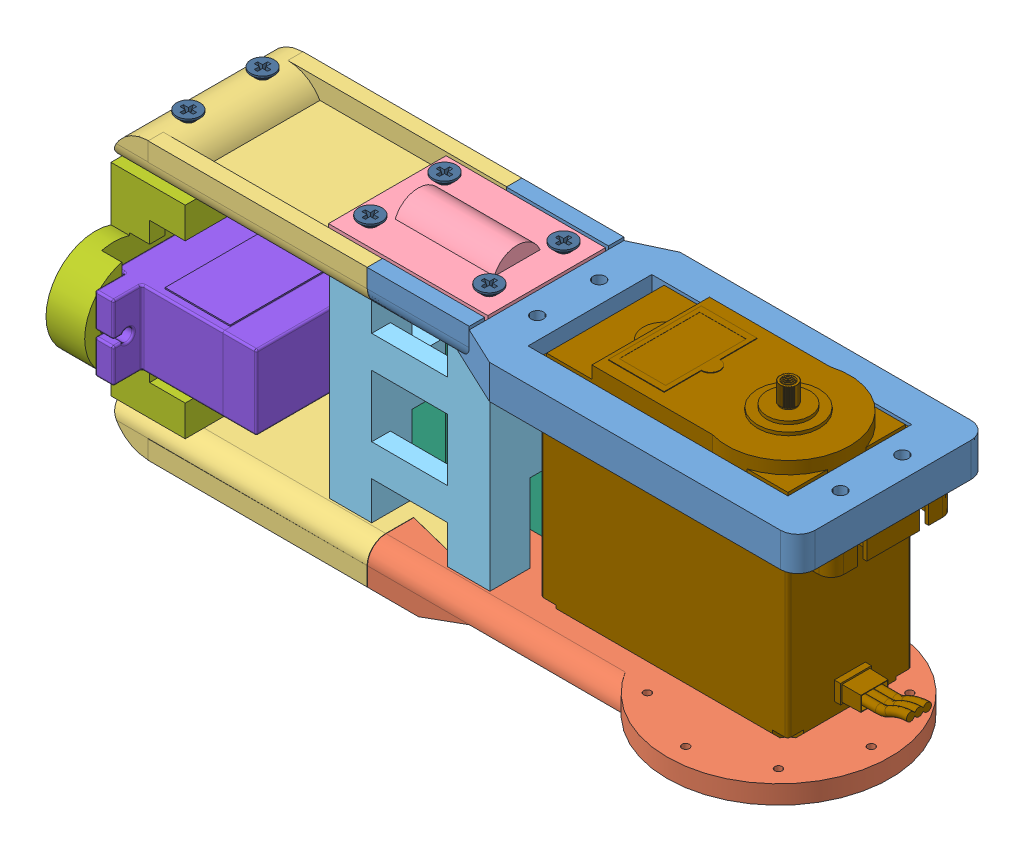
SolidWorks assembly Ensamblaje-Eslabon3, configuration Predeterminado. Lengths in mm.
Overall size (122.83 52.95 40.95).
25 component instances, 10 part files, 55 mates.
Components (placement in the parent):
- Eslabon3A-Servo-1: Eslabon3A-Servo [Predeterminado] at (-25.9252 12.8725 72.6169) size (72.49 6 30.8)
- Eslabon3B-1: Eslabon3B [Predeterminado] at (-24.576 -19.8275 72.7083) x (-0.999999 0 -0.001206) z (-0.001206 0 0.999999) size (72.01 6.5 36)
- Eslabon3C-1: Eslabon3C [Predeterminado] at (-76.6757 12.8725 72.8334) size (51.57 6.24 25.26)
- Eslabon3D-1: Eslabon3D [Predeterminado] at (-57.913 15.8725 72.2662) x (0 0 -1) z (1 0 0) size (19 5.5 25.75)
- Eslabon3E1-1: Eslabon3E1 [Predeterminado] at (-57.2515 -2.7343 81.6908) x (0 -1 0) z (0.999999 0 0.001206) size (32.7 11.9 26)
- Eslabon3E2-1: Eslabon3E2 [Predeterminado] at (-57.2293 -4.2207 63.2908) x (0 1 0) z (0.999999 0 0.001206) size (32.7 6.5 26)
- Eslabon3F-Servo-1: Eslabon3F-Servo [Predeterminado] at (-102.8295 -3.2506 77.8565) x (0 -1 0) z (0 0 1) size (32.7 12 35.5)
- Eslabon3D-2: Eslabon3D [Predeterminado] at (-57.916 -22.8275 72.7669) x (-0.001206 0 0.999999) z (0.999999 0 0.001206) size (19 5.5 25.75)
- Eslabon3C-2: Eslabon3C [Predeterminado] at (-76.668 -19.8275 72.177) x (0.999999 0 0.001206) z (0.001206 0 -0.999999) size (51.57 6.24 25.26)
- MG90S-Servo-1: MG90S-Servo [Default] at (-75.0795 -3.4758 77.742) x (0 0 -1) z (0 1 0) size (32.2 32.5 12.4)
- MG996R-Servo-1: MG996R-Servo [Default] at (-15.9295 -17.1275 72.4931) size (58.18 41.75 20)
- flat head screw_am-1: flat head screw_am [B18.6.7M - M2 x 0.4 x 13 Type I Cross Recessed FHMS --13S] at (-96.815 -26.1887 66.4931) x (0 1 0) z (-0.54958 0 0.835441) size (13 3.8 3.8)
- flat head screw_am-2: flat head screw_am [B18.6.7M - M2 x 0.4 x 13 Type I Cross Recessed FHMS --13S] at (-96.8295 -26.1887 78.4931) x (0 1 0) z (0 0 1) size (13 3.8 3.8)
- flat head screw_am-3: flat head screw_am [B18.6.7M - M2 x 0.4 x 13 Type I Cross Recessed FHMS --13S] at (-67.4295 -26.1887 78.5285) x (0 1 0) z (0 0 1) size (13 3.8 3.8)
- flat head screw_am-4: flat head screw_am [B18.6.7M - M2 x 0.4 x 13 Type I Cross Recessed FHMS --13S] at (-67.415 -26.1887 66.5286) x (0 1 0) z (0 0 1) size (13 3.8 3.8)
- flat head screw_am-5: flat head screw_am [B18.6.7M - M2 x 0.4 x 13 Type I Cross Recessed FHMS --13S] at (-48.1895 -26.1887 78.5518) x (0 1 0) z (0 0 1) size (13 3.8 3.8)
- flat head screw_am-6: flat head screw_am [B18.6.7M - M2 x 0.4 x 13 Type I Cross Recessed FHMS --13S] at (-48.1751 -26.1887 66.5518) x (0 1 0) z (0 0 1) size (13 3.8 3.8)
- flat head screw_am-7: flat head screw_am [B18.6.7M - M2 x 0.4 x 13 Type I Cross Recessed FHMS --13S] at (-96.8295 20.0187 66.4931) x (0 -1 0) z (0 0 1) size (13 3.8 3.8)
- flat head screw_am-8: flat head screw_am [B18.6.7M - M2 x 0.4 x 13 Type I Cross Recessed FHMS --13S] at (-96.8295 20.0187 78.4931) x (0 -1 0) z (0 0 1) size (13 3.8 3.8)
- flat head screw_am-9: flat head screw_am [B18.6.7M - M2 x 0.4 x 13 Type I Cross Recessed FHMS --13S] at (-67.4195 20.0187 78.4931) x (0 -1 0) z (0 0 1) size (13 3.8 3.8)
- flat head screw_am-10: flat head screw_am [B18.6.7M - M2 x 0.4 x 13 Type I Cross Recessed FHMS --13S] at (-67.4195 20.0187 66.4931) x (0 -1 0) z (-0.005668 0 0.999984) size (13 3.8 3.8)
- flat head screw_am-11: flat head screw_am [B18.6.7M - M2 x 0.4 x 13 Type I Cross Recessed FHMS --13S] at (-48.1795 20.0187 66.4931) x (0 -1 0) z (0 0 1) size (13 3.8 3.8)
- flat head screw_am-12: flat head screw_am [B18.6.7M - M2 x 0.4 x 13 Type I Cross Recessed FHMS --13S] at (-48.1795 20.0187 78.4931) x (0 -1 0) z (0 0 1) size (13 3.8 3.8)
- flat head screw_am-13: flat head screw_am [B18.6.7M - M2 x 0.4 x 13 Type I Cross Recessed FHMS --13S] at (-48.2843 -3.4775 61.7857) x (-0.001206 0 0.999999) z (-0.925311 -0.379206 -0.001116) size (13 3.8 3.8)
- flat head screw_am-14: flat head screw_am [B18.6.7M - M2 x 0.4 x 13 Type I Cross Recessed FHMS --13S] at (-67.4093 -3.4775 61.7626) x (-0.001206 0 0.999999) z (-0.925615 -0.378465 -0.001117) size (13 3.8 3.8)
Mates (geometry in assembly coordinates):
- Coincidente2: coincident: plane of Eslabon3A-Servo-1 through (-25.9252 15.8725 72.6169) normal (0 1 0); plane of Eslabon3C-1 through (-76.6757 15.8725 72.8334) normal (0 1 0)
- Coincidente3: coincident: plane of Eslabon3A-Servo-1 through (-51.4295 18.3725 64.9931) normal (-1 0 0); plane of Eslabon3C-1 through (-51.4295 15.8725 79.9806) normal (1 0 0)
- Concéntrica1: concentric: cylinder of Eslabon3A-Servo-1 through (-48.1795 18.3725 66.4931) axis (0 -1 0) radius 1; cylinder of Eslabon3D-1 through (-48.1795 18.8725 66.4931) axis (0 -1 0) radius 1
- Coincidente4: coincident: plane of Eslabon3C-1 through (-76.6757 15.8725 72.8334) normal (0 1 0); plane of Eslabon3D-1 through (-57.913 15.8725 72.2662) normal (0 -1 0)
- Paralelo1: parallel: plane of Eslabon3C-1 through (-61.3795 18.8725 82.5431) normal (0 0 -1); plane of Eslabon3D-1 through (-70.6745 18.8725 81.9931) normal (0 0 1)
- Coincidente7: coincident: plane of Eslabon3B-1 through (-7.3176 -22.8275 72.6053) normal (0 -1 0); plane of Eslabon3C-2 through (-76.668 -22.8275 72.177) normal (0 -1 0)
- Coincidente8: coincident: plane of Eslabon3D-2 through (-57.916 -22.8275 72.7669) normal (0 1 0); plane of Eslabon3C-2 through (-76.668 -22.8275 72.177) normal (0 -1 0)
- Concéntrica2: concentric: cylinder of Eslabon3D-2 through (-67.4295 -25.8275 78.5285) axis (0 1 0) radius 1; cylinder of Eslabon3C-2 through (-67.4295 -22.8275 78.5285) axis (0 1 0) radius 1
- Distancia1: distance = 0 mm: plane of Eslabon3C-2 through (-51.4133 -22.8275 65.0604) normal (0.999999 0 0.001206); plane of Eslabon3B-1 through (-51.4313 -22.8275 80.0478) normal (-0.999999 0 -0.001206)
- Coincidente15: coincident: plane of Eslabon3B-1 through (-61.3072 -22.8275 60.0359) normal (0.001206 0 -0.999999); plane of Eslabon3C-2 through (-61.3572 -25.8275 60.0359) normal (0.001206 0 -0.999999)
- Concéntrica4: concentric: cylinder of Eslabon3C-1 through (-96.8295 15.8725 78.4931) axis (0 -1 0) radius 1; cylinder of Eslabon3C-2 through (-96.8295 -22.8275 78.4931) axis (0 1 0) radius 1
- Coincidente16: coincident: plane of Eslabon3A-Servo-1 through (-61.4285 18.3725 84.9931) normal (0 0 1); plane of Eslabon3C-1 through (-61.3795 18.8725 84.9931) normal (0 0 1)
- Paralelo6: parallel: line of Eslabon3B-1 through (-61.3337 -19.8275 82.0359) axis (0.999999 0 0.001206); line of Eslabon3C-1 through (-61.3795 12.8725 81.9931) axis (-0.999999 0 -0.001206)
- Coincidente18: coincident: plane of Eslabon3A-Servo-1 through (8.2585 12.8725 85.0811) normal (0 -1 0); plane of MG996R-Servo-1 through (-42.9295 12.8725 62.4931) normal (0 1 0)
- Coincidente19: coincident: plane of Eslabon3A-Servo-1 through (4.0705 18.3725 62.4931) normal (-1 0 0); plane of MG996R-Servo-1 through (4.0705 17.8725 82.4931) normal (1 0 0)
- Coincidente20: coincident: plane of Eslabon3A-Servo-1 through (-37.9295 18.3725 82.4931) normal (0 0 -1); plane of MG996R-Servo-1 through (-35.9295 17.8725 82.4931) normal (0 0 1)
- Coincidente21: coincident: plane of Eslabon3E1-1 through (-57.2371 -2.7343 69.7908) normal (0.001206 0 -0.999999); plane of Eslabon3E2-1 through (-57.2371 -4.2207 69.7908) normal (-0.001206 0 0.999999)
- Coincidente22: coincident: plane of Eslabon3E1-1 through (-51.738 12.8725 75.1975) normal (0 1 0); plane of Eslabon3E2-1 through (-44.8565 12.8725 69.8058) normal (0 1 0)
- Coincidente23: coincident: plane of Eslabon3E1-1 through (-44.863 12.8725 75.2058) normal (0.999999 0 0.001206); plane of Eslabon3E2-1 through (-44.8565 -19.8275 69.8058) normal (0.999999 0 0.001206)
- Paralelo8: parallel: plane of Eslabon3D-2 through (-70.6658 -25.8275 63.0246) normal (0.001206 0 -0.999999); plane of Eslabon3C-2 through (-61.3602 -25.8275 62.4859) normal (-0.001206 0 0.999999)
- Concéntrica8: concentric: cylinder of Eslabon3E2-1 through (-67.415 15.5725 66.5285) axis (0 -1 0) radius 1; cylinder of Eslabon3C-2 through (-67.415 -22.8275 66.5285) axis (0 1 0) radius 1
- Paralelo9: parallel: plane of Eslabon3E1-1 through (-57.2515 -2.7343 81.6908) normal (-0.001206 0 0.999999); plane of Eslabon3C-2 through (-61.3874 -25.8275 85.0358) normal (-0.001206 0 0.999999)
- Coincidente29: coincident: plane of Eslabon3C-1 through (-76.6757 12.8725 72.8334) normal (0 -1 0); plane of Eslabon3E1-1 through (-70.863 12.8725 75.1744) normal (0 1 0)
- Coincidente30: coincident: plane of Eslabon3B-1 through (-7.3176 -19.8275 72.6053) normal (0 1 0); plane of Eslabon3E1-1 through (-44.863 -19.8275 75.2058) normal (0 -1 0)
- Concéntrica10: concentric: cylinder of Eslabon3F-Servo-1 through (-99.8295 -3.4758 72.492) axis (-1 0 0) radius 5.9982; cylinder of MG90S-Servo-1 through (-104.0795 -3.4758 72.492) axis (1 0 0) radius 5.75
- Coincidente31: coincident: plane of Eslabon3F-Servo-1 through (-96.5795 -3.2506 77.8565) normal (1 0 0); plane of MG90S-Servo-1 through (-96.5795 -3.4758 77.742) normal (-1 0 0)
- Paralelo10: parallel: plane of Eslabon3F-Servo-1 through (-96.5795 -14.8275 82.4931) normal (0 1 0); plane of MG90S-Servo-1 through (-93.5795 -9.4758 89.242) normal (0 -1 0)
- Coincidente33: coincident: plane of Eslabon3C-1 through (-76.6757 12.8725 72.8334) normal (0 -1 0); plane of Eslabon3F-Servo-1 through (-99.8295 12.8725 59.9931) normal (0 1 0)
- Concéntrica11: concentric: cylinder of Eslabon3C-1 through (-96.8295 15.8725 66.4931) axis (0 -1 0) radius 1; cylinder of Eslabon3F-Servo-1 through (-96.8295 1.5225 66.4931) axis (0 1 0) radius 1
- Concéntrica12: concentric: cylinder of Eslabon3F-Servo-1 through (-96.8295 -8.4775 78.4931) axis (0 -1 0) radius 1; cylinder of Eslabon3C-2 through (-96.8295 -22.8275 78.4931) axis (0 1 0) radius 1
- Concéntrica13: concentric: cylinder of Eslabon3C-2 through (-96.8295 -22.8275 78.4931) axis (0 1 0) radius 1; cone of flat head screw_am-2 through (-96.8295 -25.8887 78.4931) axis (0 1 0)
- Concéntrica14: concentric: cylinder of Eslabon3D-2 through (-67.4295 -25.8275 78.5285) axis (0 1 0) radius 1; cone of flat head screw_am-3 through (-67.4295 -25.8887 78.5285) axis (0 1 0)
- Concéntrica15: concentric: cylinder of Eslabon3D-2 through (-67.415 -25.8275 66.5286) axis (0 1 0) radius 1; cone of flat head screw_am-4 through (-67.415 -25.8887 66.5286) axis (0 1 0)
- Concéntrica16: concentric: cylinder of Eslabon3D-2 through (-48.1895 -25.8275 78.5518) axis (0 1 0) radius 1; cone of flat head screw_am-5 through (-48.1895 -25.8887 78.5518) axis (0 1 0)
- Concéntrica17: concentric: cylinder of Eslabon3D-2 through (-48.1751 -25.8275 66.5518) axis (0 1 0) radius 1; cone of flat head screw_am-6 through (-48.1751 -25.8887 66.5518) axis (0 1 0)
- Concéntrica18: concentric: cylinder of Eslabon3C-1 through (-96.8295 15.8725 66.4931) axis (0 -1 0) radius 1; cone of flat head screw_am-7 through (-96.8295 19.7187 66.4931) axis (0 -1 0)
- Concéntrica19: concentric: cylinder of Eslabon3C-1 through (-96.8295 15.8725 78.4931) axis (0 -1 0) radius 1; cone of flat head screw_am-8 through (-96.8295 19.7187 78.4931) axis (0 -1 0)
- Concéntrica20: concentric: cylinder of Eslabon3D-1 through (-67.4195 18.8725 78.4931) axis (0 -1 0) radius 1; cone of flat head screw_am-9 through (-67.4195 19.7187 78.4931) axis (0 -1 0)
- Concéntrica21: concentric: cylinder of Eslabon3D-1 through (-67.4195 18.8725 66.4931) axis (0 -1 0) radius 1; cone of flat head screw_am-10 through (-67.4195 19.7187 66.4931) axis (0 -1 0)
- Concéntrica22: concentric: cylinder of Eslabon3D-1 through (-48.1795 18.8725 66.4931) axis (0 -1 0) radius 1; cone of flat head screw_am-11 through (-48.1795 19.7187 66.4931) axis (0 -1 0)
- Concéntrica23: concentric: cylinder of Eslabon3D-1 through (-48.1795 18.8725 78.4931) axis (0 -1 0) radius 1; cone of flat head screw_am-12 through (-48.1795 19.7187 78.4931) axis (0 -1 0)
- Coincidente34: coincident: axis of Eslabon3E1-1 through (-48.294 -3.4775 69.8016) axis (-0.001206 0 0.999999); axis of flat head screw_am-13 through (-48.2847 -3.4775 62.0857) axis (-0.001206 0 0.999999)
- Coincidente35: coincident: axis of Eslabon3E1-1 through (-67.419 -3.4775 69.7785) axis (-0.001206 0 0.999999); axis of flat head screw_am-14 through (-67.4097 -3.4775 62.0626) axis (-0.001206 0 0.999999)
- Coincidente36: coincident: plane of flat head screw_am-13 through (-48.2843 -3.4775 61.7857) normal (0.001206 0 -0.999999); plane of flat head screw_am-14 through (-67.4093 -3.4775 61.7626) normal (0.001206 0 -0.999999)
- Coincidente37: coincident: axis of Eslabon3C-2 through (-96.815 -25.8275 66.4931) axis (0 1 0); axis of flat head screw_am-1 through (-96.815 -25.8887 66.4931) axis (0 1 0)
- Coincidente38: coincident: plane of flat head screw_am-1 through (-96.815 -26.1887 66.4931) normal (0 -1 0); point of flat head screw_am-2
- Coincidente39: coincident: plane of flat head screw_am-1 through (-96.815 -26.1887 66.4931) normal (0 -1 0); plane of flat head screw_am-3 through (-67.4295 -26.1887 78.5285) normal (0 -1 0)
- Coincidente40: coincident: plane of flat head screw_am-3 through (-67.4295 -26.1887 78.5285) normal (0 -1 0); plane of flat head screw_am-4 through (-67.415 -26.1887 66.5286) normal (0 -1 0)
- Coincidente41: coincident: point of flat head screw_am-4; plane of flat head screw_am-5 through (-48.1895 -26.1887 78.5518) normal (0 -1 0)
- Coincidente42: coincident: plane of flat head screw_am-4 through (-67.415 -26.1887 66.5286) normal (0 -1 0); plane of flat head screw_am-6 through (-48.1751 -26.1887 66.5518) normal (0 -1 0)
- Coincidente43: coincident: plane of flat head screw_am-7 through (-96.8295 20.0187 66.4931) normal (0 1 0); plane of flat head screw_am-10 through (-67.4195 20.0187 66.4931) normal (0 1 0)
- Coincidente44: coincident: plane of flat head screw_am-8 through (-96.8295 20.0187 78.4931) normal (0 1 0); plane of flat head screw_am-9 through (-67.4195 20.0187 78.4931) normal (0 1 0)
- Coincidente45: coincident: plane of flat head screw_am-9 through (-67.4195 20.0187 78.4931) normal (0 1 0); plane of flat head screw_am-12 through (-48.1795 20.0187 78.4931) normal (0 1 0)
- Coincidente46: coincident: plane of flat head screw_am-11 through (-48.1795 20.0187 66.4931) normal (0 1 0); plane of flat head screw_am-12 through (-48.1795 20.0187 78.4931) normal (0 1 0)
- Coincidente47: coincident: plane of flat head screw_am-10 through (-67.4195 20.0187 66.4931) normal (0 1 0); plane of flat head screw_am-12 through (-48.1795 20.0187 78.4931) normal (0 1 0)
